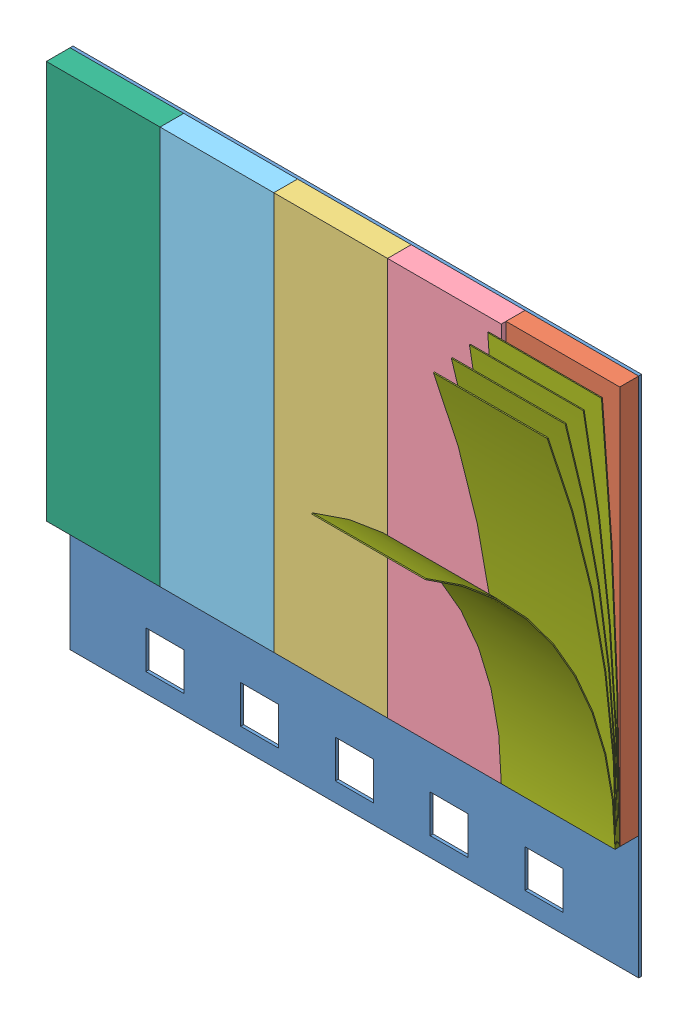
SolidWorks assembly toppad, configuration Default. Lengths in mm.
Overall size (76.2 69.85 28.98).
11 component instances, 7 part files, 30 mates.
Components (placement in the parent):
- notebase-1: notebase [Default] at (58.5511 8.6332 63.7533) size (76.2 69.85 0.4)
- blue5-1: blue5 [Default] at (58.5511 78.4832 64.1502) x (1 0 0) z (0 -1 0) size (15.24 2.54 53.34)
- green5-1: green5 [Default] at (12.8311 25.1432 64.1502) x (-1 0 0) z (0 1 0) size (15.24 3.17 53.34)
- orange5-1: orange5 [Default] at (28.0711 25.1432 64.1502) x (-1 0 0) z (0 1 0) size (15.24 3.17 53.34)
- pink5-1: pink5 [Default] at (-2.4089 25.1432 64.1502) x (-1 0 0) z (0 1 0) size (15.24 3.17 53.34)
- yellow5-1: yellow5 [Default] at (-17.6489 25.1432 64.1502) x (-1 0 0) z (0 1 0) size (15.24 3.17 53.34)
- bluecurved-4: bluecurved [60deg] at (43.3111 25.1432 67.1982) x (-1 0 0) z (0 1 0) size (15.24 25.53 44.11)
- bluecurved-5: bluecurved [20deg] at (43.3111 25.1432 67.0712) x (-1 0 0) z (0 1 0) size (15.24 9.33 52.26)
- bluecurved-3: bluecurved [15deg] at (43.3111 25.1432 66.9442) x (-1 0 0) z (0 1 0) size (15.24 7.07 52.73)
- bluecurved-6: bluecurved [10deg] at (43.3111 25.1432 66.8172) x (-1 0 0) z (0 1 0) size (15.24 4.77 53.07)
- bluecurved-7: bluecurved [5deg] at (43.3111 25.1432 66.6902) x (-1 0 0) z (0 1 0) size (15.24 2.45 53.27)
Mates (geometry in assembly coordinates):
- Coincident1: coincident anti-aligned: plane of blue5-1 through (43.3111 25.1432 64.1502) normal (-1 0 0); plane of orange5-1 through (43.3111 78.4832 64.1502) normal (1 0 0)
- Coincident2: coincident aligned: plane of blue5-1 through (58.5511 25.1432 64.1502) normal (0 0 -1); plane of orange5-1 through (28.0711 78.4832 64.1502) normal (0 0 -1)
- Coincident3: coincident aligned: plane of blue5-1 through (58.5511 25.1432 64.1502) normal (0 -1 0); plane of orange5-1 through (28.0711 25.1432 64.1502) normal (0 -1 0)
- Coincident4: coincident aligned: plane of green5-1 through (12.8311 78.4832 64.1502) normal (0 0 -1); plane of orange5-1 through (28.0711 78.4832 64.1502) normal (0 0 -1)
- Coincident5: coincident anti-aligned: plane of green5-1 through (28.0711 78.4832 64.1502) normal (1 0 0); plane of orange5-1 through (28.0711 78.4832 64.1502) normal (-1 0 0)
- Coincident6: coincident aligned: plane of green5-1 through (12.8311 78.4832 64.1502) normal (0 1 0); plane of orange5-1 through (28.0711 78.4832 64.1502) normal (0 1 0)
- Coincident7: coincident aligned: plane of green5-1 through (12.8311 78.4832 64.1502) normal (0 1 0); plane of pink5-1 through (-2.4089 78.4832 64.1502) normal (0 1 0)
- Coincident8: coincident aligned: plane of green5-1 through (12.8311 78.4832 64.1502) normal (0 0 -1); plane of pink5-1 through (-2.4089 78.4832 64.1502) normal (0 0 -1)
- Coincident10: coincident anti-aligned: plane of green5-1 through (12.8311 78.4832 64.1502) normal (-1 0 0); plane of pink5-1 through (12.8311 78.4832 64.1502) normal (1 0 0)
- Coincident11: coincident anti-aligned: plane of pink5-1 through (-2.4089 78.4832 64.1502) normal (-1 0 0); plane of yellow5-1 through (-2.4089 78.4832 64.1502) normal (1 0 0)
- Coincident12: coincident aligned: plane of pink5-1 through (-2.4089 78.4832 64.1502) normal (0 0 -1); plane of yellow5-1 through (-17.6489 78.4832 64.1502) normal (0 0 -1)
- Coincident13: coincident aligned: plane of pink5-1 through (-2.4089 78.4832 64.1502) normal (0 1 0); plane of yellow5-1 through (-17.6489 78.4832 64.1502) normal (0 1 0)
- Coincident16: coincident aligned: plane of notebase-1 through (58.5511 8.6332 64.1502) normal (1 0 0); plane of blue5-1 through (58.5511 25.1432 64.1502) normal (1 0 0)
- Coincident18: coincident anti-aligned: plane of notebase-1 through (58.5511 8.6332 64.1502) normal (0 0 1); plane of blue5-1 through (58.5511 25.1432 64.1502) normal (0 0 -1)
- Coincident19: coincident aligned: plane of notebase-1 through (58.5511 78.4832 64.1502) normal (0 1 0); plane of blue5-1 through (58.5511 78.4832 64.1502) normal (0 1 0)
- Coincident24: coincident aligned: plane of blue5-1 through (58.5511 25.1432 64.1502) normal (1 0 0); plane of bluecurved1-4 through (58.5511 78.2128 71.4602) normal (1 0 0)
- Coincident25: coincident aligned: plane of blue5-1 through (58.5511 25.1432 64.1502) normal (0 -1 0); plane of bluecurved1-4 through (43.3111 25.1432 66.8172) normal (0 -1 0)
- Coincident26: coincident anti-aligned: line of bluecurved1-3 through (58.5511 25.1432 66.9442) axis (-1 0 0); line of bluecurved1-4 through (43.3111 25.1432 66.9442) axis (1 0 0)
- Coincident27: coincident aligned: plane of blue5-1 through (58.5511 25.1432 64.1502) normal (1 0 0); plane of bluecurved1-3 through (58.5511 77.8759 73.8866) normal (1 0 0)
- Coincident28: coincident aligned: plane of blue5-1 through (58.5511 25.1432 64.1502) normal (0 -1 0); plane of bluecurved1-3 through (43.3111 25.1432 66.9442) normal (0 -1 0)
- Coincident29: coincident anti-aligned: line of bluecurved1-2 through (58.5511 25.1432 67.0712) axis (-1 0 0); line of bluecurved1-3 through (43.3111 25.1432 67.0712) axis (1 0 0)
- Coincident31: coincident aligned: plane of blue5-1 through (58.5511 25.1432 64.1502) normal (1 0 0); plane of bluecurved1-2 through (58.5511 77.4065 76.2867) normal (1 0 0)
- Coincident32: coincident aligned: plane of blue5-1 through (58.5511 25.1432 64.1502) normal (0 -1 0); plane of bluecurved1-2 through (43.3111 25.1432 67.0712) normal (0 -1 0)
- Coincident33: coincident aligned: plane of blue5-1 through (58.5511 25.1432 64.1502) normal (0 -1 0); plane of bluecurved1-1 through (43.3111 25.1432 67.1982) normal (0 -1 0)
- Coincident34: coincident aligned: plane of blue5-1 through (58.5511 25.1432 64.1502) normal (1 0 0); plane of bluecurved1-1 through (58.5511 69.255 92.6662) normal (1 0 0)
- Coincident35: coincident anti-aligned: line of bluecurved1-1 through (58.5511 25.1432 67.1982) axis (-1 0 0); line of bluecurved1-2 through (43.3111 25.1432 67.1982) axis (1 0 0)
- Coincident36: coincident aligned: line of blue5-1 through (58.5511 25.1432 66.6902) axis (-1 0 0); line of bluecurved1-5 through (58.5511 25.1432 66.6902) axis (-1 0 0)
- Coincident37: coincident aligned: plane of blue5-1 through (58.5511 25.1432 64.1502) normal (0 -1 0); plane of bluecurved1-5 through (43.3111 25.1432 66.6902) normal (0 -1 0)
- Coincident38: coincident aligned: plane of blue5-1 through (58.5511 25.1432 64.1502) normal (1 0 0); plane of bluecurved1-5 through (58.5511 78.4155 69.0161) normal (1 0 0)
- Coincident39: coincident anti-aligned: line of bluecurved1-4 through (58.5511 25.1432 66.8172) axis (-1 0 0); line of bluecurved1-5 through (43.3111 25.1432 66.8172) axis (1 0 0)
